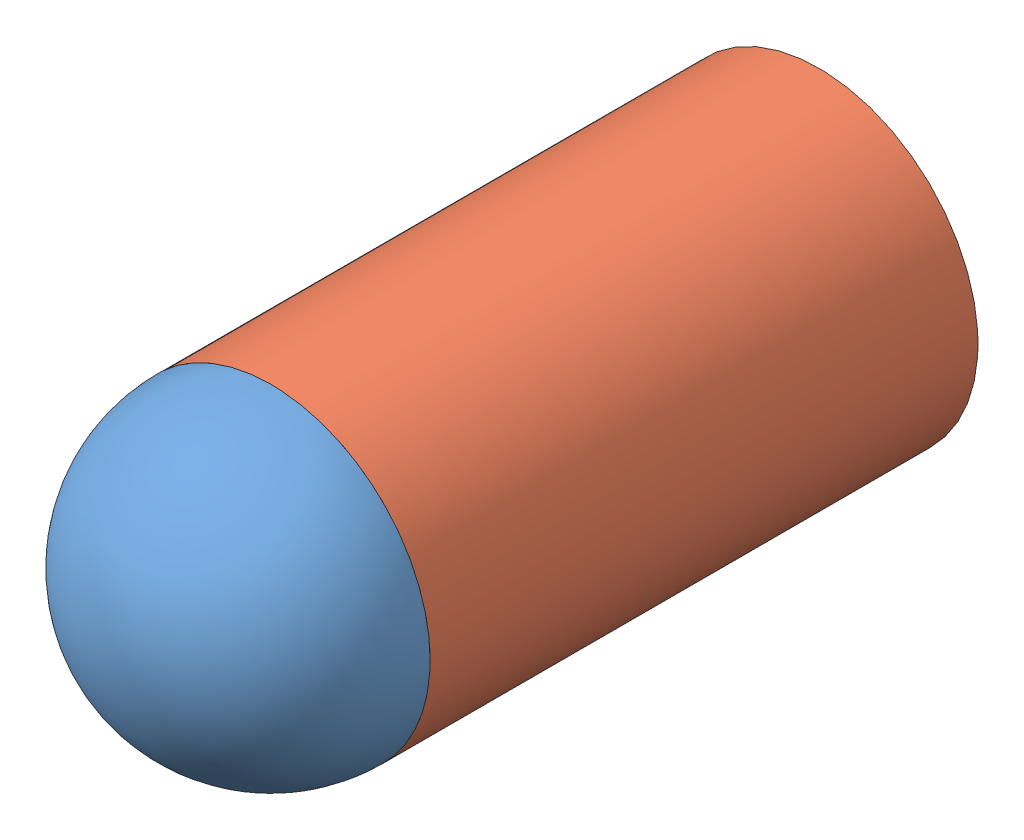
SolidWorks assembly Assem1, configuration Default. Lengths in mm.
Overall size (46.5 46.5 103.25).
2 component instances, 2 part files, 2 mates.
Components (placement in the parent):
- Face-1: Face [Default] at (-28.1505 21.0578 61.8863) size (46.5 46.5 38.25)
- Body-1: Body [Default] at (-28.1505 21.0578 -3.1137) size (46.5 46.5 80)
Mates (geometry in assembly coordinates):
- Coincident1: coincident: plane of Face-1 through (-28.1505 21.0578 61.8863) normal (0 0 -1); plane of Body-1 through (-28.1505 21.0578 61.8863) normal (0 0 1)
- Concentric1: concentric anti-aligned: cylinder of Face-1 through (-28.1505 21.0578 76.8863) axis (0 0 -1) radius 15; cylinder of Body-1 through (-28.1505 21.0578 61.8863) axis (0 0 1) radius 15
